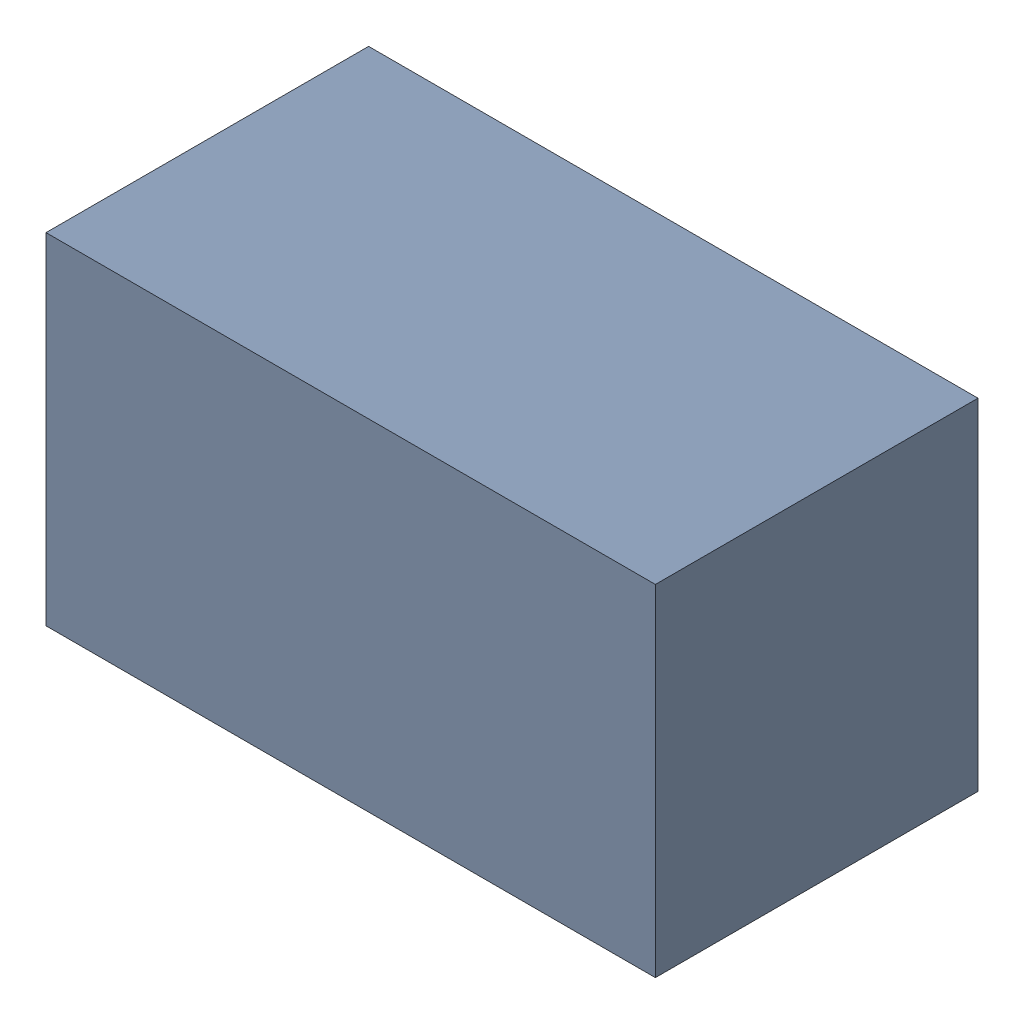
SolidWorks assembly R26, configuration Standard. Lengths in mm.
Overall size (1.7 0.95 0.9).
2 component instances, 1 part files, 0 mates.
Components (placement in the parent):
- 885541288-1: 885541288 [Standard] at (15.5 15.98 0) size (1.7 0.95 0.9)
  - Extruded_10-1: Extruded_10 [Standard] at origin size (1.7 0.95 0.9)
